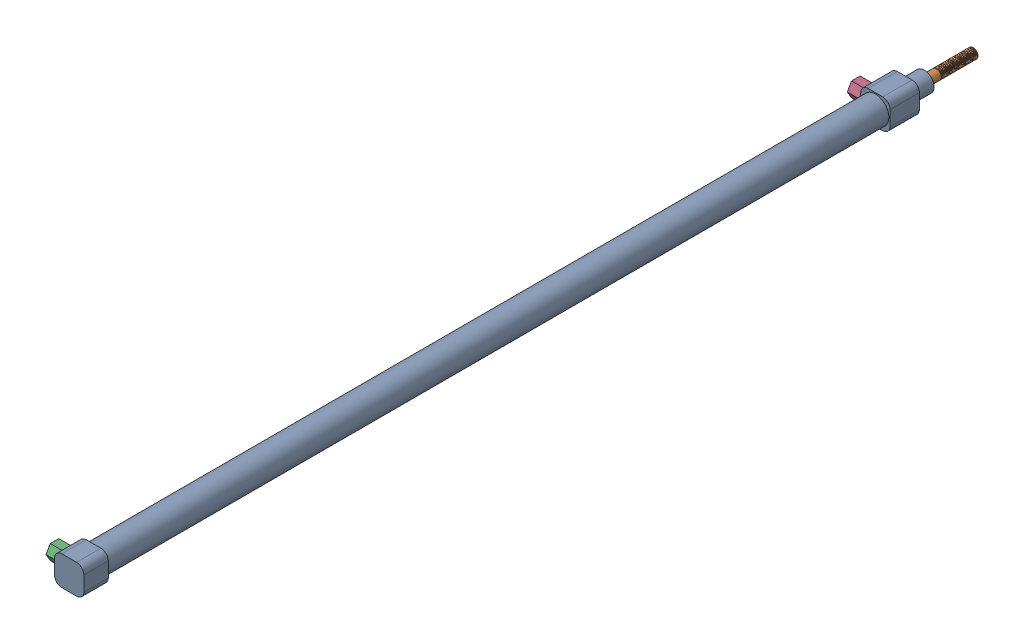
SolidWorks assembly 2210-300气缸装配体, configuration Default. Lengths in mm.
Overall size (18.68 13.36 370.02).
4 component instances, 3 part files, 4 mates.
Components (placement in the parent):
- 22气缸10-300-1: 22气缸10-300 [默认] at (121.2568 174.2105 124.3424) size (12 12 350)
- 22气缸杆10-300-1: 22气缸杆10-300 [默认] at (121.2568 174.2105 444.3424) x (0.899953 0.435988 0) z (0 0 -1) size (10 10 360.02)
- 22气缸嘴10-300-1: 22气缸嘴10-300 [默认] at (118.2568 174.2105 448.3424) x (0 0 -1) z (-1 0 0) size (7 6.07 9)
- 22气缸嘴10-300-2: 22气缸嘴10-300 [默认] at (118.2568 174.2105 120.3424) x (0 0 -1) z (-1 0 0) size (7 6.07 9)
Mates (geometry in assembly coordinates):
- 同心1: concentric: cylinder of assembly; cylinder of assembly; cylinder of 22气缸10-300-1 through (118.2568 174.2105 448.3424) axis (-1 0 0) radius 2; cylinder of 22气缸嘴10-300-1 through (115.2568 174.2105 448.3424) axis (1 0 0) radius 2
- 重合1: coincident: plane of assembly; plane of assembly; plane of 22气缸10-300-1 through (118.2568 174.2105 448.3424) normal (-1 0 0); plane of 22气缸嘴10-300-1 through (118.2568 174.2105 448.3424) normal (1 0 0)
- 同心2: concentric: cylinder of assembly; cylinder of assembly; cylinder of 22气缸10-300-1 through (118.2568 174.2105 120.3424) axis (-1 0 0) radius 2; cylinder of 22气缸嘴10-300-2 through (115.2568 174.2105 120.3424) axis (1 0 0) radius 2
- 重合2: coincident: plane of assembly; plane of assembly; plane of 22气缸10-300-1 through (118.2568 174.2105 120.3424) normal (-1 0 0); plane of 22气缸嘴10-300-2 through (118.2568 174.2105 120.3424) normal (1 0 0)
